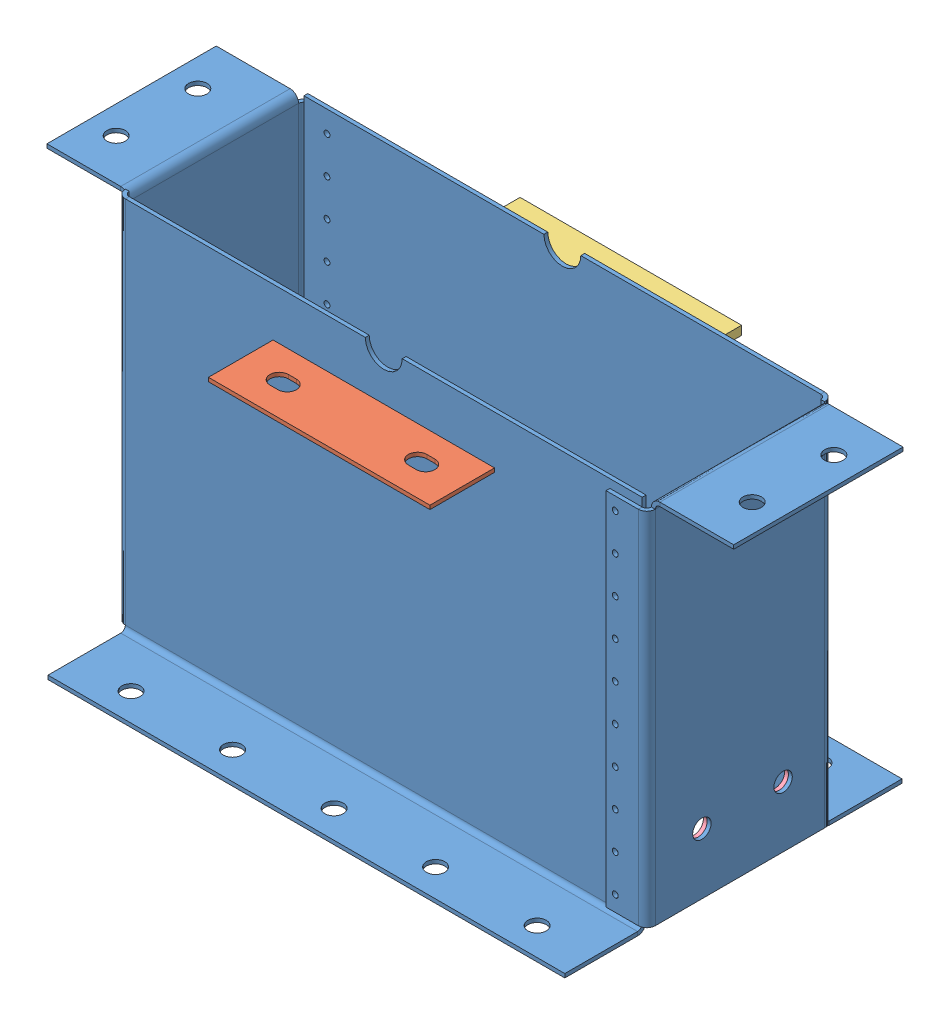
SolidWorks assembly Bottom Assembly 2.0, configuration Default. Lengths in mm.
Overall size (475.21 259.83 232.03).
5 component instances, 4 part files, 13 mates.
Components (placement in the parent):
- Bottom Assembly - Casing Side 1-1: Bottom Assembly - Casing Side 1 [Default] at (-69.1764 26.1218 352.4726) size (415.41 259.83 181.44)
- Bottom Assembly - Casing Side 1-2: Bottom Assembly - Casing Side 1 [Default] at (286.4236 26.1218 226.9432) x (-1 0 0) z (0 0 -1) size (415.41 259.83 181.44)
- Bottom Assembly - Bearing Stand-1: Bottom Assembly - Bearing Stand [Default] at (32.4236 246.8224 396.9226) size (152.4 2.66 44.45)
- Bottom Assembly - Bearing Stand Back Side-1: Bottom Assembly - Bearing Stand Back Side [Default] at (32.4236 246.8224 226.9432) size (152.4 6.07 44.45)
- Bottom Assembly - Mesh - New Design-1: Bottom Assembly - Mesh - New Design [Default] at (-72.3514 102.3218 348.9801) size (361.95 53.46 119.38)
Mates (geometry in assembly coordinates):
- Coincident10: coincident anti-aligned: plane of Bottom Assembly - Casing Side 1-2 through (108.6236 280.1218 226.9432) normal (0 0 -1); plane of Bottom Assembly - Casing Side 1-1 through (-69.1764 26.1218 226.9432) normal (0 0 1)
- Parallel1: parallel anti-aligned: line of Bottom Assembly - Casing Side 1-1 through (95.9236 280.1218 349.8157) axis (-1 0 0); line of Bottom Assembly - Casing Side 1-2 through (-69.1764 280.1218 229.6001) axis (1 0 0)
- Coincident16: coincident anti-aligned: line of Bottom Assembly - Casing Side 1-1 through (-46.9514 26.1218 226.9432) axis (-1 0 0); line of Bottom Assembly - Casing Side 1-2 through (-69.1764 26.1218 226.9432) axis (1 0 0)
- Coincident17: coincident aligned: line of Bottom Assembly - Casing Side 1-1 through (-69.1764 26.1218 226.9432) axis (0 1 0); line of Bottom Assembly - Casing Side 1-2 through (-69.1764 26.1218 226.9432) axis (0 1 0)
- Coincident18: coincident anti-aligned: line of Bottom Assembly - Casing Side 1-1 through (32.4236 246.8224 352.4726) axis (1 0 0); line of Bottom Assembly - Bearing Stand-1 through (184.8236 246.8224 352.4726) axis (-1 0 0)
- Coincident19: coincident: point of assembly; point of Bottom Assembly - Casing Side 1-1; point of Bottom Assembly - Bearing Stand-1
- Coincident24: coincident anti-aligned: plane of Bottom Assembly - Casing Side 1-1 through (108.6236 280.1218 352.4726) normal (0 0 1); plane of Bottom Assembly - Bearing Stand-1 through (32.4236 244.1656 352.4726) normal (0 0 -1)
- Coincident25: coincident: point of assembly; point of Bottom Assembly - Casing Side 1-2; moEndPointRef_w of Bottom Assembly - Bearing Stand Back Side-1
- Coincident26: coincident anti-aligned: line of Bottom Assembly - Casing Side 1-2 through (184.8236 246.8224 226.9432) axis (-1 0 0); line of Bottom Assembly - Bearing Stand Back Side-1 through (32.4236 246.8224 226.9432) axis (1 0 0)
- Coincident27: coincident anti-aligned: plane of Bottom Assembly - Casing Side 1-2 through (108.6236 280.1218 226.9432) normal (0 0 -1); plane of Bottom Assembly - Bearing Stand Back Side-1 through (32.4236 240.7493 226.9432) normal (0 0 1)
- Coincident28: coincident anti-aligned: line of Bottom Assembly - Casing Side 1-2 through (-69.1764 102.3218 229.6001) axis (1 0 0); line of Bottom Assembly - Mesh - New Design-1 through (283.7668 102.3218 229.6001) axis (-1 0 0)
- Coincident29: coincident anti-aligned: plane of Bottom Assembly - Casing Side 1-1 through (-72.3514 26.1218 352.4726) normal (1 0 0); plane of Bottom Assembly - Mesh - New Design-1 through (-72.3514 102.3218 348.9801) normal (-1 0 0)
- Parallel2: parallel anti-aligned: plane of Bottom Assembly - Casing Side 1-1 through (108.6236 280.1218 349.8157) normal (0 0 -1); plane of Bottom Assembly - Mesh - New Design-1 through (-72.3514 99.665 348.9801) normal (0 0 1)
